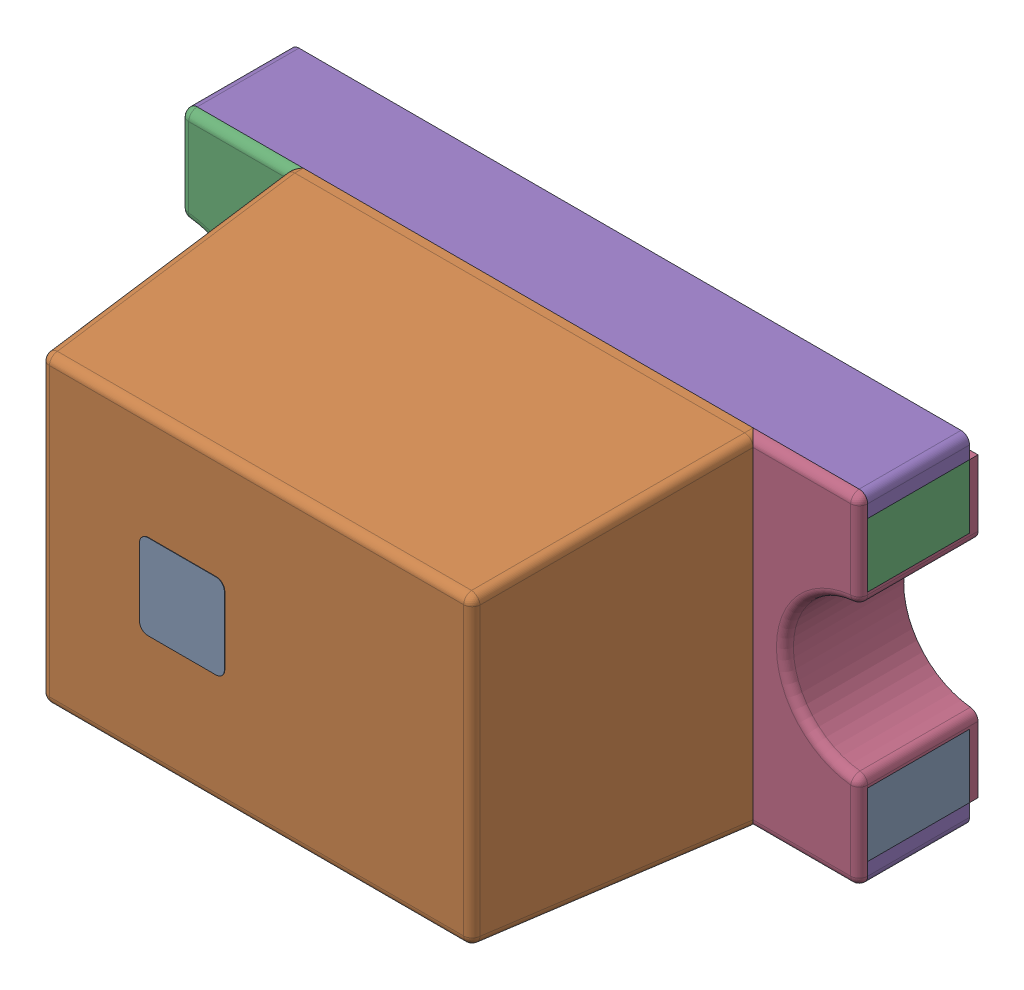
SolidWorks assembly Diode_Lite-On_LTST-C190GKT_eec.step, configuration Default. Lengths in mm.
Overall size (1.6 0.8 0.9).
7 component instances, 7 part files, 0 mates.
Components (placement in the parent):
- 1-4.step-1: 1-4.step [Default] at (-0.1749 0.0038 0.001) size (0.2 0.2 0.05)
- 2-5.step-1: 2-5.step [Default] at origin size (1.1 0.8 0.64)
- 3-6.step-1: 3-6.step [Default] at origin size (1.6 0.8 0.28)
- 4.step-1: 4.step [Default] at origin size (1.6 0.8 0.24)
- Lite-On_Logo_Adjustable.step-1: Lite-On_Logo_Adjustable.step [Default] at (-0.9132 -0.3001 -1.9175) x (1 0 0) z (0 -1 0) size (0.21 0.05 0.1)
- 5.step-1: 5.step [Default] at origin size (1.6 0.7 0.24)
- 6.step-1: 6.step [Default] at origin size (1.6 0.15 0.24)
